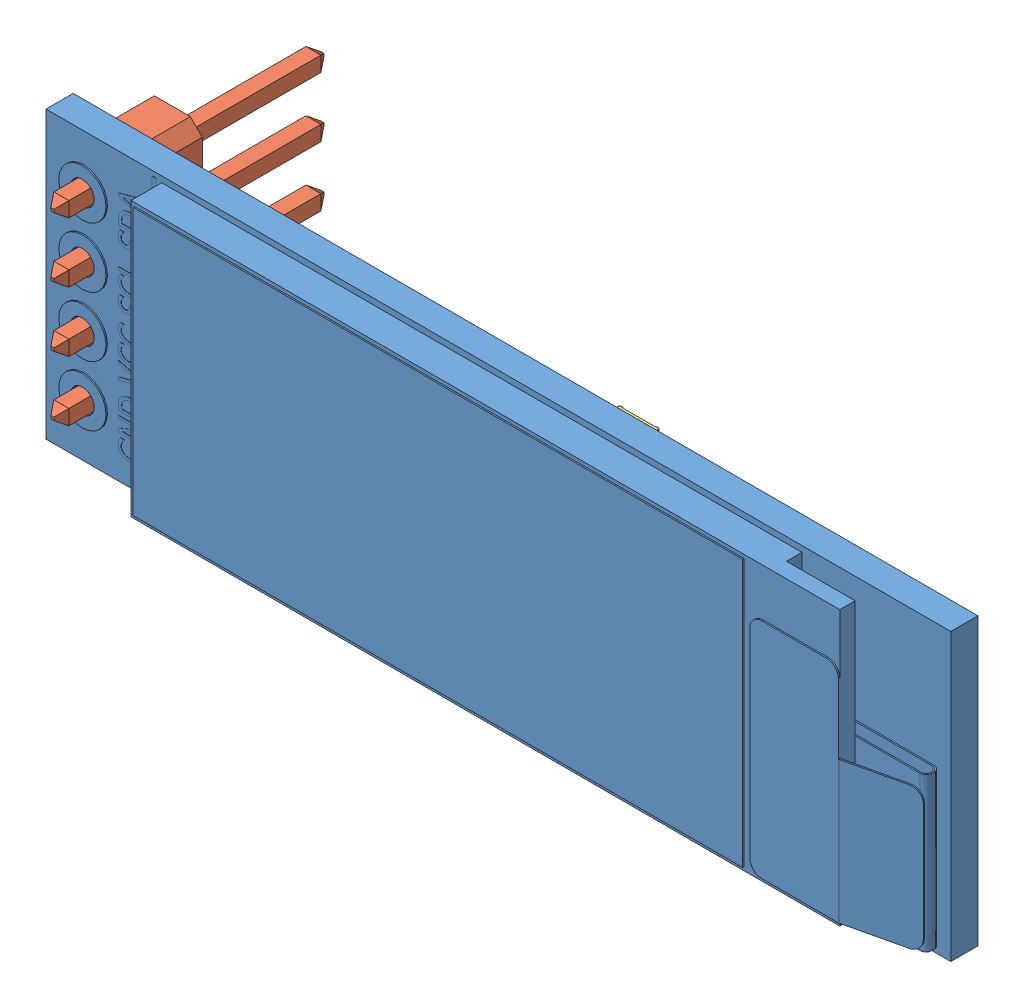
SolidWorks assembly SSD1306_OLED_0.91_128x32, configuration Default. Lengths in mm.
Overall size (38.3 12.1 20.1).
17 component instances, 4 part files, 0 mates.
Components (placement in the parent):
- SSD1306_OLED_0.91_128x32.stp-1: SSD1306_OLED_0.91_128x32.stp [Default] at origin size (38.3 12.1 11.46)
  - OLED_0.91_128x32.stp-1: OLED_0.91_128x32.stp [Default] at origin size (38.3 12.1 2.57)
  - Pin Header 4 x 1 TH 2.54mm Pitch.stp-1: Pin Header 4 x 1 TH 2.54mm Pitch.stp [Default] at (-17.55 -3.81 -2.6) size (2.54 10.16 11.43)
  - RESC-0603.stp-1: RESC-0603.stp [Default] at (4.3 -5.3 0) x (1 0 0) z (0 0 -1) size (1.7 0.9 0.55)
  - RESC-0603.stp-2: RESC-0603.stp [Default] at (4.3 -3.8 0) x (1 0 0) z (0 0 -1) size (1.7 0.9 0.55)
  - RESC-0603.stp-3: RESC-0603.stp [Default] at (4.3 -2.3 0) x (1 0 0) z (0 0 -1) size (1.7 0.9 0.55)
  - RESC-0603.stp-4: RESC-0603.stp [Default] at (4.3 -0.8 0) x (1 0 0) z (0 0 -1) size (1.7 0.9 0.55)
  - RESC-0603.stp-5: RESC-0603.stp [Default] at (4.3 0.7 0) x (1 0 0) z (0 0 -1) size (1.7 0.9 0.55)
  - RESC-0603.stp-6: RESC-0603.stp [Default] at (4.3 2.2 0) x (1 0 0) z (0 0 -1) size (1.7 0.9 0.55)
  - RESC-0603.stp-7: RESC-0603.stp [Default] at (4.3 3.7 0) x (1 0 0) z (0 0 -1) size (1.7 0.9 0.55)
  - RESC-0603.stp-8: RESC-0603.stp [Default] at (4.3 5.2 0) x (1 0 0) z (0 0 -1) size (1.7 0.9 0.55)
  - RESC-0603.stp-9: RESC-0603.stp [Default] at (-1.4 -3.06 0) x (1 0 0) z (0 0 -1) size (1.7 0.9 0.55)
  - RESC-0603.stp-10: RESC-0603.stp [Default] at (-1.4 -1.56 0) x (1 0 0) z (0 0 -1) size (1.7 0.9 0.55)
  - RESC-0603.stp-11: RESC-0603.stp [Default] at (-1.4 -0.06 0) x (1 0 0) z (0 0 -1) size (1.7 0.9 0.55)
  - RESC-0603.stp-12: RESC-0603.stp [Default] at (-1.4 1.44 0) x (1 0 0) z (0 0 -1) size (1.7 0.9 0.55)
  - RESC-0603.stp-13: RESC-0603.stp [Default] at (-1.4 2.94 0) x (1 0 0) z (0 0 -1) size (1.7 0.9 0.55)
  - 2SD0601A.stp-1: 2SD0601A.stp [Default] at (-9.8 -1.3 -0.08) x (1 0 0) z (0 1 0) size (2.76 1.18 2.9)
